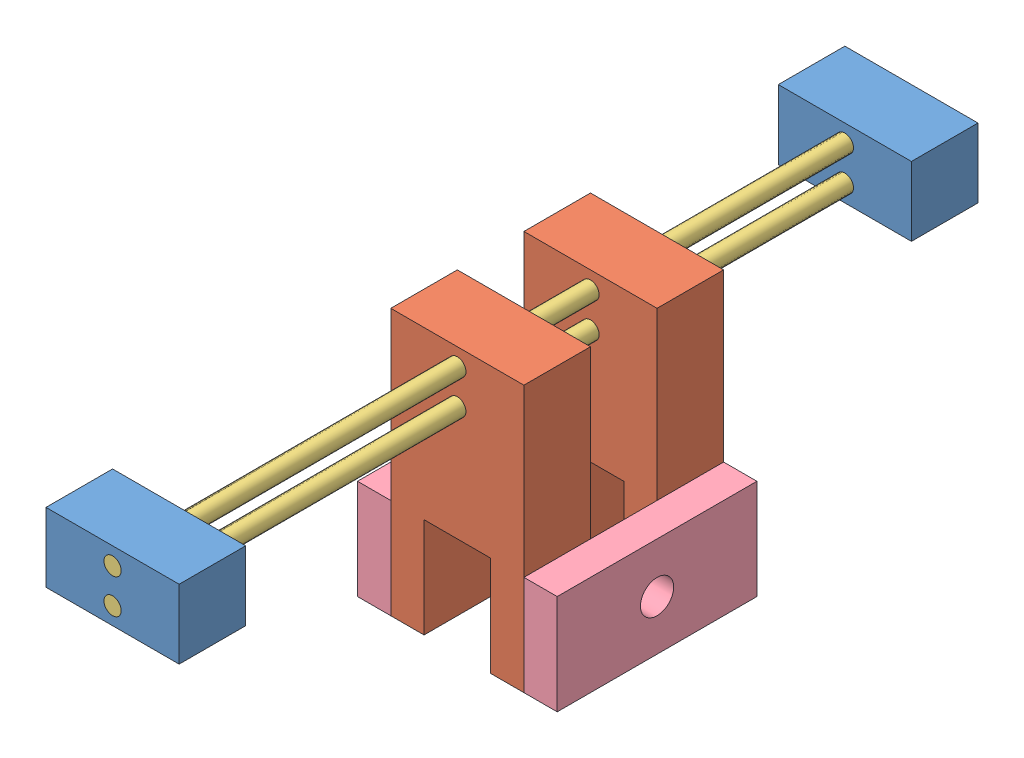
SolidWorks assembly Wheel assembly 2.0, configuration Default. Lengths in mm.
Overall size (76.2 101.6 304.8).
8 component instances, 4 part files, 24 mates.
Components (placement in the parent):
- Pillow Block 2.0-1: Pillow Block 2.0 [Default] at (20.6407 31.0632 35.0144) size (50.8 26.42 25.4)
- Pillow Block 2.0-2: Pillow Block 2.0 [Default] at (20.6407 31.0632 314.4144) size (50.8 26.42 25.4)
- Wheel Holder 2.0-1: Wheel Holder 2.0 [Default] at (20.6407 -44.1208 182.8676) size (50.8 101.6 25.4)
- Wheel Holder 2.0-2: Wheel Holder 2.0 [Default] at (20.6407 -44.1208 132.0676) size (50.8 101.6 25.4)
- Leadscrew 2.0-2: Leadscrew 2.0 [Default] at (46.0407 37.6672 35.0144) size (6.6 6.6 304.8)
- Leadscrew 2.0-3: Leadscrew 2.0 [Default] at (46.0407 50.8752 35.0144) size (6.6 6.6 304.8)
- Shoulder Bearing 2.0-1: Shoulder Bearing 2.0 [Default] at (84.1407 -44.1208 132.0676) x (0 0 1) z (-1 0 0) size (76.2 38.1 12.7)
- Shoulder Bearing 2.0-2: Shoulder Bearing 2.0 [Default] at (7.9407 -44.1208 208.2676) x (0 0 -1) z (1 0 0) size (76.2 38.1 12.7)
Mates (geometry in assembly coordinates):
- Concentric3: concentric aligned: cylinder of Pillow Block 2.0-2 through (46.0407 50.8752 339.8144) axis (0 0 -1) radius 3.302; cylinder of Leadscrew 2.0-3 through (46.0407 50.8752 339.8144) axis (0 0 -1) radius 3.302
- Concentric4: concentric aligned: cylinder of Pillow Block 2.0-1 through (46.0407 50.8752 60.4144) axis (0 0 -1) radius 3.302; cylinder of Leadscrew 2.0-3 through (46.0407 50.8752 339.8144) axis (0 0 -1) radius 3.302
- Coincident4: coincident aligned: plane of Pillow Block 2.0-2 through (20.6407 31.0632 339.8144) normal (0 0 1); circle of Leadscrew 2.0-3
- Coincident5: coincident aligned: plane of Pillow Block 2.0-1 through (20.6407 31.0632 35.0144) normal (0 0 -1); plane of Leadscrew 2.0-3 through (46.0407 50.8752 35.0144) normal (0 0 -1)
- Concentric6: concentric aligned: cylinder of Pillow Block 2.0-2 through (46.0407 37.6672 339.8144) axis (0 0 -1) radius 3.302; cylinder of Leadscrew 2.0-2 through (46.0407 37.6672 339.8144) axis (0 0 -1) radius 3.302
- Coincident6: coincident aligned: plane of Pillow Block 2.0-2 through (20.6407 31.0632 339.8144) normal (0 0 1); plane of Leadscrew 2.0-2 through (46.0407 37.6672 339.8144) normal (0 0 1)
- Concentric7: concentric aligned: cylinder of Pillow Block 2.0-1 through (46.0407 37.6672 60.4144) axis (0 0 -1) radius 3.302; cylinder of Leadscrew 2.0-2 through (46.0407 37.6672 339.8144) axis (0 0 -1) radius 3.302
- Coincident7: coincident aligned: plane of Pillow Block 2.0-1 through (20.6407 31.0632 35.0144) normal (0 0 -1); plane of Leadscrew 2.0-2 through (46.0407 37.6672 35.0144) normal (0 0 -1)
- Concentric8: concentric aligned: cylinder of Wheel Holder 2.0-1 through (46.0407 37.6672 208.2676) axis (0 0 -1) radius 3.302; cylinder of Leadscrew 2.0-2 through (46.0407 37.6672 339.8144) axis (0 0 -1) radius 3.302
- Concentric9: concentric aligned: cylinder of Wheel Holder 2.0-1 through (46.0407 50.8752 208.2676) axis (0 0 -1) radius 3.302; cylinder of Leadscrew 2.0-3 through (46.0407 50.8752 339.8144) axis (0 0 -1) radius 3.302
- Concentric10: concentric aligned: cylinder of Wheel Holder 2.0-2 through (46.0407 37.6672 157.4676) axis (0 0 -1) radius 3.302; cylinder of Leadscrew 2.0-2 through (46.0407 37.6672 339.8144) axis (0 0 -1) radius 3.302
- Concentric11: concentric aligned: cylinder of Wheel Holder 2.0-2 through (46.0407 50.8752 157.4676) axis (0 0 -1) radius 3.302; cylinder of Leadscrew 2.0-3 through (46.0407 50.8752 339.8144) axis (0 0 -1) radius 3.302
- Parallel1: parallel aligned: plane of Pillow Block 2.0-1 through (20.6407 57.4792 60.4144) normal (0 1 0); plane of Wheel Holder 2.0-2 through (20.6407 57.4792 157.4676) normal (0 1 0)
- Parallel2: parallel aligned: plane of Pillow Block 2.0-2 through (20.6407 57.4792 339.8144) normal (0 1 0); plane of Wheel Holder 2.0-1 through (20.6407 57.4792 208.2676) normal (0 1 0)
- Coincident8: coincident anti-aligned: plane of Wheel Holder 2.0-1 through (71.4407 -44.1208 208.2676) normal (1 0 0); plane of Shoulder Bearing 2.0-1 through (71.4407 -44.1208 132.0676) normal (-1 0 0)
- Coincident9: coincident anti-aligned: plane of Wheel Holder 2.0-1 through (71.4407 -44.1208 208.2676) normal (1 0 0); plane of Shoulder Bearing 2.0-1 through (71.4407 -44.1208 132.0676) normal (-1 0 0)
- Coincident10: coincident aligned: line of Wheel Holder 2.0-1 through (71.4407 -44.1208 208.2676) axis (0 1 0); line of Shoulder Bearing 2.0-1 through (71.4407 -44.1208 208.2676) axis (0 1 0)
- Coincident11: coincident anti-aligned: plane of Wheel Holder 2.0-1 through (20.6407 -44.1208 208.2676) normal (-1 0 0); plane of Shoulder Bearing 2.0-2 through (20.6407 -44.1208 208.2676) normal (1 0 0)
- Coincident12: coincident anti-aligned: line of Wheel Holder 2.0-1 through (20.6407 -44.1208 208.2676) axis (0 1 0); line of Shoulder Bearing 2.0-2 through (20.6407 -6.0208 208.2676) axis (0 -1 0)
- Coincident13: coincident aligned: plane of Wheel Holder 2.0-1 through (20.6407 -44.1208 208.2676) normal (0 -1 0); plane of Shoulder Bearing 2.0-2 through (20.6407 -44.1208 208.2676) normal (0 -1 0)
- Coincident14: coincident aligned: plane of Wheel Holder 2.0-1 through (20.6407 -44.1208 208.2676) normal (0 -1 0); plane of Shoulder Bearing 2.0-1 through (71.4407 -44.1208 132.0676) normal (0 -1 0)
- Parallel3: parallel aligned: line of Wheel Holder 2.0-2 through (20.6407 -44.1208 132.0676) axis (0 1 0); line of Shoulder Bearing 2.0-2 through (7.9407 -44.1208 132.0676) axis (0 1 0)
- Coincident16: coincident aligned: plane of Wheel Holder 2.0-2 through (20.6407 -44.1208 132.0676) normal (0 0 -1); plane of Shoulder Bearing 2.0-2 through (20.6407 -44.1208 132.0676) normal (0 0 -1)
- Coincident17: coincident aligned: plane of Wheel Holder 2.0-2 through (20.6407 -44.1208 132.0676) normal (0 0 -1); plane of Shoulder Bearing 2.0-1 through (71.4407 -44.1208 132.0676) normal (0 0 -1)
